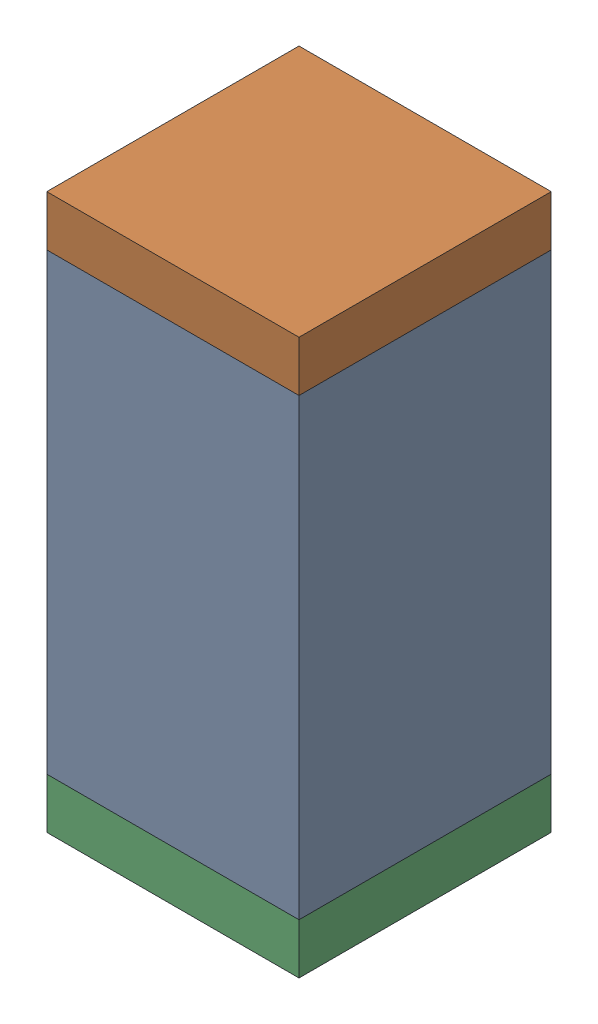
SolidWorks assembly C67, configuration Default. Lengths in mm.
Overall size (0.5 1.1 0.5).
6 component instances, 2 part files, 0 mates.
Components (placement in the parent):
- 791586336-1: 791586336 [Default] at (112 55.25 0) size (0.5 0.9 0.5)
  - Extruded_8-1: Extruded_8 [Default] at origin size (0.5 0.9 0.5)
- 810157360-1: 810157360 [Default] at (112 55.75 0) size (0.5 0.1 0.5)
  - Extruded_9-1: Extruded_9 [Default] at origin size (0.5 0.1 0.5)
- 810157360-2: 810157360 [Default] at (112 54.75 0) size (0.5 0.1 0.5)
  - Extruded_9-1: Extruded_9 [Default] at origin size (0.5 0.1 0.5)
